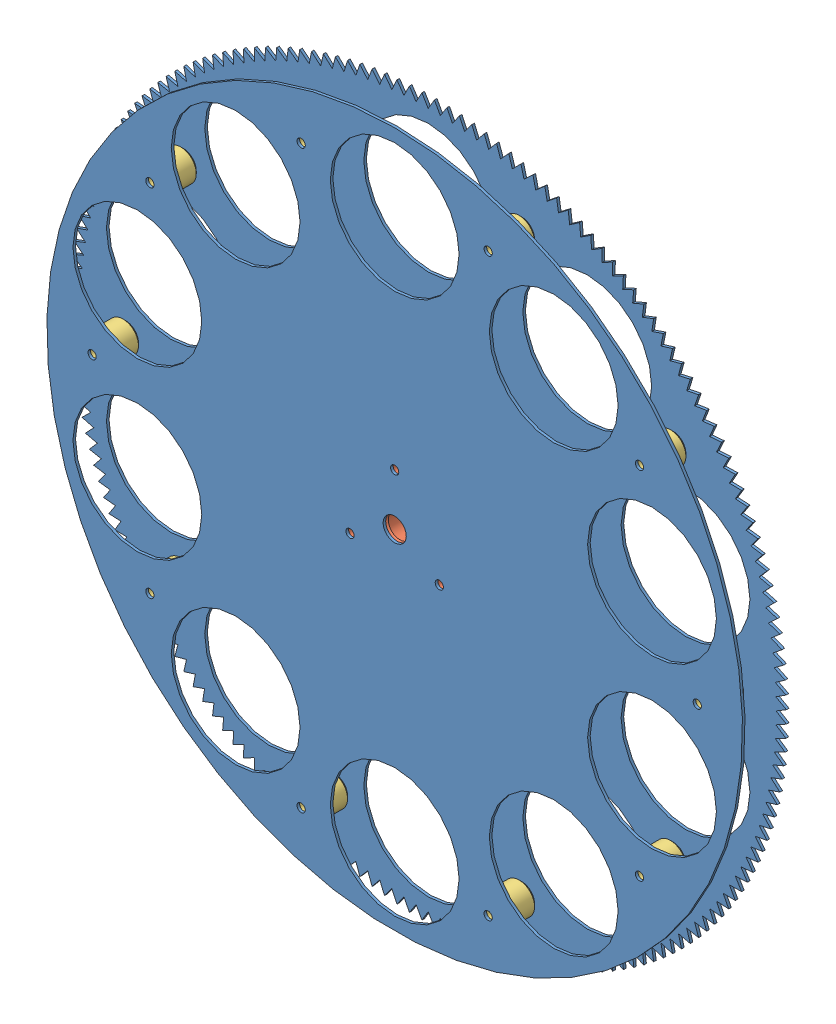
SolidWorks assembly Wheel Assembly, configuration Default. Lengths in mm.
Overall size (278.08 278.08 14).
13 component instances, 3 part files, 12 mates.
Components (placement in the parent):
- Ferris Plate-1: Ferris Plate [Default] at (0 0 -7) x (1 0 0) z (0 1 0) size (278.08 1 278.08)
- Center Spacer-1: Center Spacer [Default] at origin size (46.64 42 12)
- Perimeter Spacer-1: Perimeter Spacer [Default] at (-36.288 111.683 6) x (0 -1 0) z (0 0 -1) size (12 12 12)
- Perimeter Spacer-2: Perimeter Spacer [Default] at (-95.0032 69.0239 6) x (0.587785 -0.809017 0) z (0 0 -1) size (12 12 12)
- Perimeter Spacer-3: Perimeter Spacer [Default] at (-117.4305 0 6) x (0.951057 -0.309017 0) z (0 0 -1) size (12 12 12)
- Perimeter Spacer-4: Perimeter Spacer [Default] at (-95.0032 -69.0239 6) x (0.951057 0.309017 0) z (0 0 -1) size (12 12 12)
- Perimeter Spacer-5: Perimeter Spacer [Default] at (-36.288 -111.683 6) x (0.587785 0.809017 0) z (0 0 -1) size (12 12 12)
- Perimeter Spacer-6: Perimeter Spacer [Default] at (36.288 -111.683 6) x (0 1 0) z (0 0 -1) size (12 12 12)
- Perimeter Spacer-7: Perimeter Spacer [Default] at (95.0032 -69.0239 6) x (-0.587785 0.809017 0) z (0 0 -1) size (12 12 12)
- Perimeter Spacer-8: Perimeter Spacer [Default] at (117.4305 0 6) x (-0.951057 0.309017 0) z (0 0 -1) size (12 12 12)
- Perimeter Spacer-9: Perimeter Spacer [Default] at (95.0032 69.0239 6) x (-0.951057 -0.309017 0) z (0 0 -1) size (12 12 12)
- Perimeter Spacer-10: Perimeter Spacer [Default] at (36.288 111.683 6) x (-0.587785 -0.809017 0) z (0 0 -1) size (12 12 12)
- Ferris Plate-2: Ferris Plate [Toothless] at (0 0 7) x (-1 0 0) z (0 1 0) size (270 1 270)
Mates (geometry in assembly coordinates):
- Coincident2: coincident aligned: plane of Ferris Plate-1 through (0 0 -7) normal (0 1 0); plane of assembly through (0 0 0) normal (0 1 0)
- Coincident3: coincident aligned: plane of Ferris Plate-1; plane of assembly through (0 0 0) normal (1 0 0)
- Concentric1: concentric anti-aligned: circle of Ferris Plate-1; circle of Center Spacer-1
- Concentric2: concentric anti-aligned: circle of Ferris Plate-1; circle of Center Spacer-1
- Coincident6: coincident anti-aligned: plane of Ferris Plate-1 through (0 0 -6) normal (0 0 1); plane of Center Spacer-1 through (0 0 -6) normal (0 0 -1)
- Concentric3: concentric aligned: circle of Ferris Plate-1; circle of Perimeter Spacer-1
- Coincident7: coincident anti-aligned: plane of Ferris Plate-1 through (0 0 -6) normal (0 0 1); plane of Perimeter Spacer-1 through (-36.288 111.683 -6) normal (0 0 -1)
- Parallel1: parallel anti-aligned: plane of Perimeter Spacer-1; plane of assembly through (0 0 0) normal (1 0 0)
- Coincident10: coincident aligned: plane of Ferris Plate-1 through (0 0 -7) normal (0 1 0); plane of Ferris Plate-2 through (0 0 7) normal (0 1 0)
- Coincident11: coincident anti-aligned: plane of Ferris Plate-1; plane of Ferris Plate-2
- Coincident12: coincident anti-aligned: plane of Center Spacer-1 through (0 0 6) normal (0 0 1); plane of Ferris Plate-2 through (0 0 6) normal (0 0 -1)
- Coincident14: coincident aligned: plane of Center Spacer-1 through (0 0 0) normal (0 0 1); plane of assembly through (0 0 0) normal (0 0 1)
